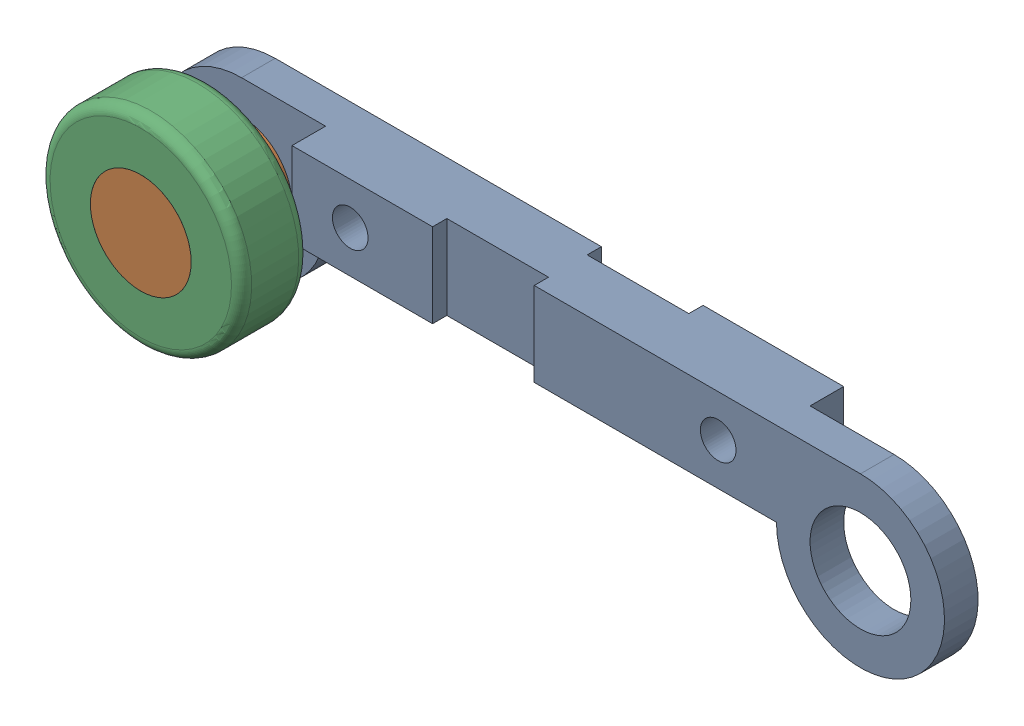
SolidWorks assembly Chain assemble, configuration Default. Lengths in mm.
Overall size (259.18 79.97 45).
3 component instances, 3 part files, 4 mates.
Components (placement in the parent):
- Chain-1: Chain [Default] at (-3.8537 34.5138 234.2) size (244.2 50 20)
- Pin-1: Pin [Varsayılan] at (-100.9537 9.5138 234.2) x (-0.812681 0.582709 0) z (0 0 1) size (40 40 45)
- Step wheel-1: Step wheel [Varsayılan] at (-100.9537 9.5138 254.2) x (0.429903 0.902875 0) z (0 0 1) size (60 60 20)
Mates (geometry in assembly coordinates):
- Concentric1: concentric aligned: cylinder of Pin-1 through (-100.9537 9.5138 274.2) axis (0 0 -1) radius 15; cylinder of Teker-1 through (-100.9537 9.5138 274.2) axis (0 0 -1) radius 15
- Coincident1: coincident anti-aligned: plane of Zincir-1 through (-100.9537 9.5138 234.2) normal (0 0 -1); plane of Pin-1 through (-100.9537 9.5138 234.2) normal (0 0 1)
- Concentric2: concentric aligned: cylinder of Zincir-1 through (-100.9537 9.5138 254.2) axis (0 0 -1) radius 15; cylinder of Pin-1 through (-100.9537 9.5138 274.2) axis (0 0 -1) radius 15
- Coincident2: coincident anti-aligned: plane of Zincir-1 through (-100.9537 9.5138 254.2) normal (0 0 1); plane of Teker-1 through (-100.9537 9.5138 254.2) normal (0 0 -1)
